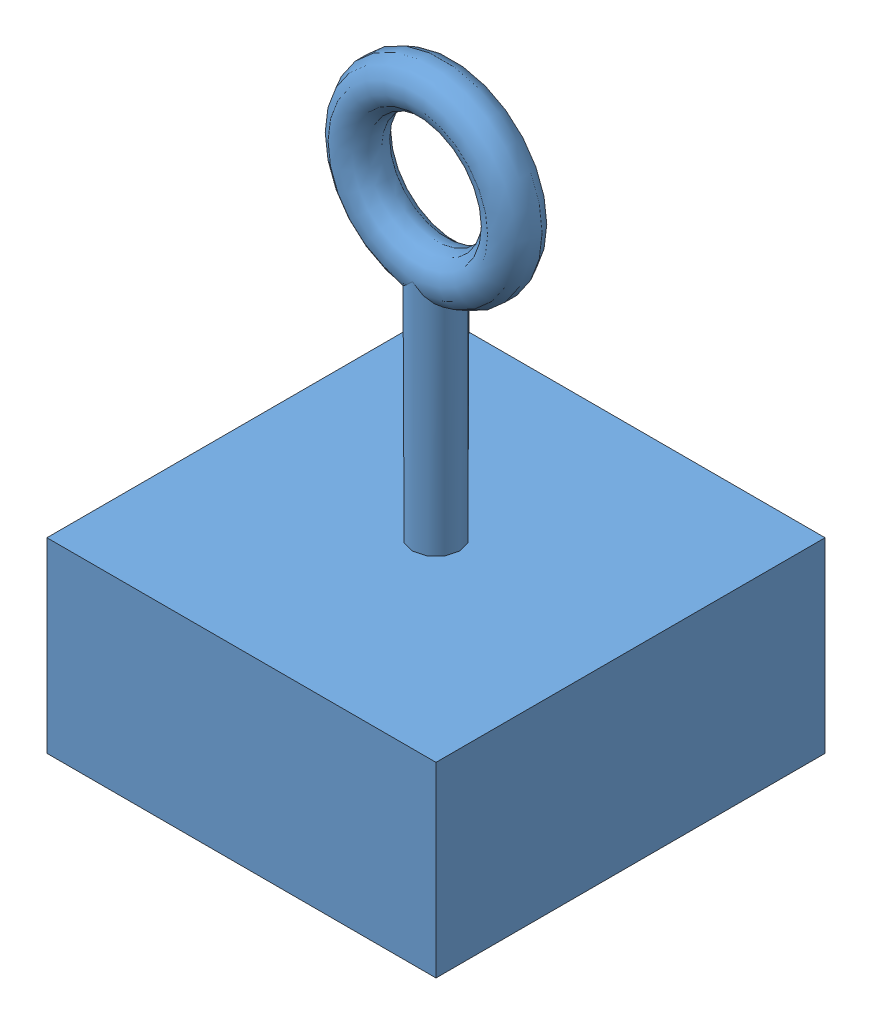
SolidWorks assembly skeleton_assy, configuration Default. Lengths in mm.
Overall size (75 120.8 75).
2 component instances, 2 part files, 6 mates.
Components (placement in the parent):
- mount-1: mount [Default] at origin size (25 38.5 25)
- Skeleton_9-1: Skeleton_9 [Default] at (0.2 -37.3 0.2) x (0 0 -1) z (-1 0 0) size (75 95 75)
Mates (geometry in assembly coordinates):
- Coincident1: coincident aligned: plane of mount-1 through (0 0 0) normal (0 0 1)
- Coincident2: coincident aligned: plane of mount-1 through (0 0 0) normal (0 1 0)
- Coincident3: coincident aligned: plane of mount-1 through (0 0 0) normal (1 0 0)
- Coincident4: coincident anti-aligned: plane of mount-1 through (0 0 0) normal (0 -1 0); plane of Skeleton_9-1 through (0.2 0 0.2) normal (0 1 0)
- Coincident5: coincident anti-aligned: plane of mount-1 through (12.5 12 -12.5) normal (0 0 -1); plane of Skeleton_9-1 through (-12.5 0 -12.5) normal (0 0 1)
- Coincident6: coincident anti-aligned: plane of mount-1 through (-12.5 12 12.5) normal (-1 0 0); plane of Skeleton_9-1 through (-12.5 0 12.9) normal (1 0 0)
